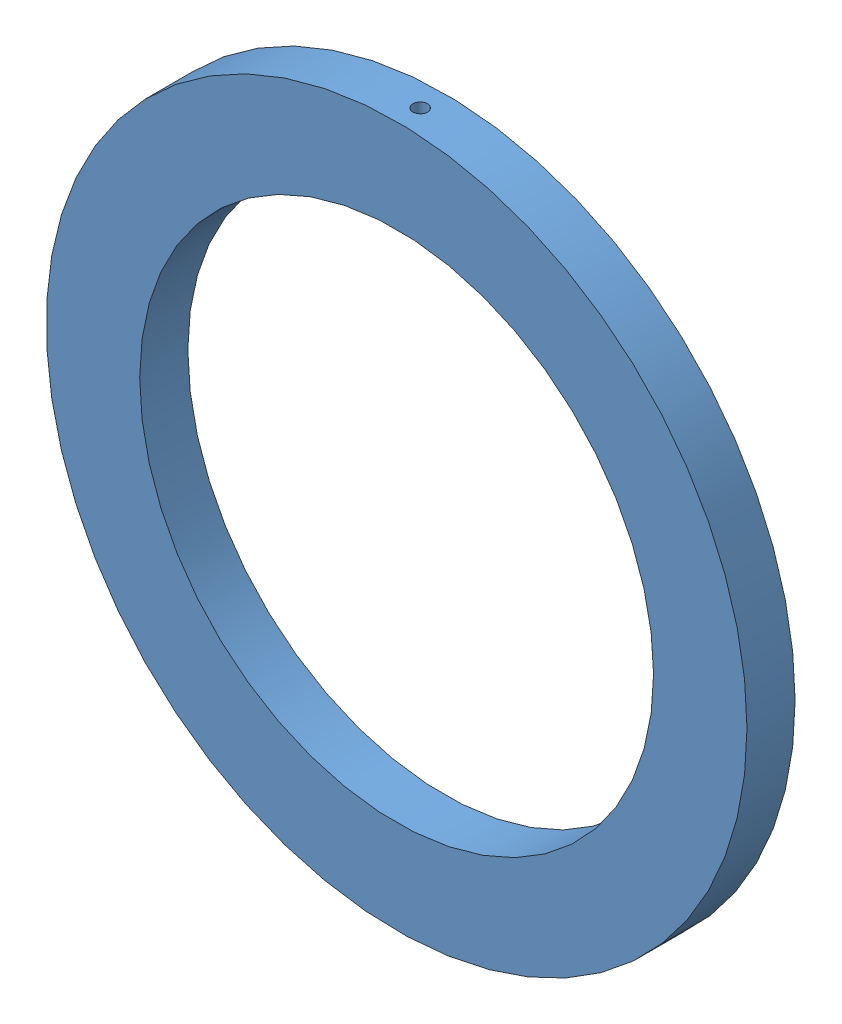
SolidWorks assembly GAS_RING_MONOMER, configuration Default. Lengths in mm.
Overall size (57.15 57.15 3.92).
3 component instances, 3 part files, 4 mates.
Components (placement in the parent):
- GAS_RING_TOP_v2-2: GAS_RING_TOP_v2 [Default] at origin size (57.15 57.15 3.92)
- GAS_RING_BOTTOM-1: GAS_RING_BOTTOM [Default] at (0 0 -1.6764) (suppressed, hidden)
- PEEK_GAS_INSULATOR-1: PEEK_GAS_INSULATOR [Default] at (0 0 -3.5814) (suppressed, hidden)
Mates (geometry in assembly coordinates):
- Coincident1: coincident aligned: axis of GAS_RING_TOP_v2-2 through (0 0 -1.3589) axis (0 0 1); axis of GAS_RING_BOTTOM-1 through (0 0 -1.9939) axis (0 0 1)
- Coincident2: coincident anti-aligned: circle of GAS_RING_TOP_v2-2; circle of GAS_RING_BOTTOM-1
- Coincident3: coincident aligned: axis of GAS_RING_TOP_v2-2 through (0 0 -1.9622) axis (0 0 1); axis of PEEK_GAS_INSULATOR-1 through (0 0 -4.3561) axis (0 0 1)
- Coincident4: coincident aligned: circle of GAS_RING_BOTTOM-1; plane of PEEK_GAS_INSULATOR-1 through (0 0 -1.9939) normal (0 0 1)
